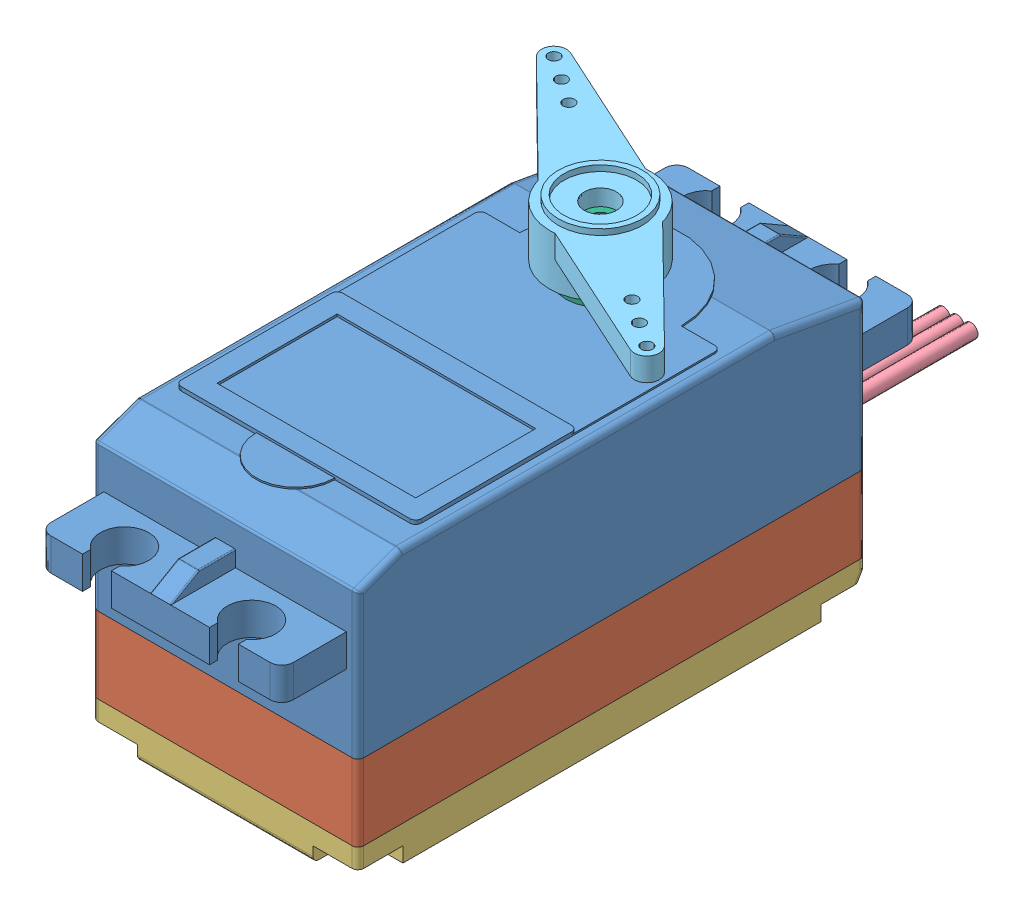
SolidWorks assembly MYSTERY SDS-S0070, ANALOG SERVO, configuration Default. Lengths in mm.
Overall size (32.51 30.1 69).
10 component instances, 7 part files, 17 mates.
Components (placement in the parent):
- MYSTERY SDS-S0070, ANALOG SERVO, MAIN BODY, TOP-1: MYSTERY SDS-S0070, ANALOG SERVO, MAIN BODY, TOP [Default] at origin size (23 14.34 55.2)
- MYSTERY SDS-S0070, ANALOG SERVO, MAIN BODY, MIDDLE-1: MYSTERY SDS-S0070, ANALOG SERVO, MAIN BODY, MIDDLE [Default] at (0 -3.3 0) size (23 6.6 44)
- MYSTERY SDS-S0070, ANALOG SERVO, MAIN BODY, BOTTOM-1: MYSTERY SDS-S0070, ANALOG SERVO, MAIN BODY, BOTTOM [Default] at (0 -9.6 0) size (23 3 44)
- MYSTERY SDS-S0070, ANALOG SERVO, CONNECTOR-1: MYSTERY SDS-S0070, ANALOG SERVO, CONNECTOR [Default] at (0 -4.55 -22) size (6.8 4.1 19.4)
- MYSTERY SDS-S0070, ANALOG SERVO, HORN-1: MYSTERY SDS-S0070, ANALOG SERVO, HORN [Default] at (0 15.6 -10.5) x (0.566638 0 -0.823967) z (0.823967 0 0.566638) size (8.8 4.9 33.4)
- MYSTERY SDS-S0070, ANALOG SERVO, SHAFT-1: MYSTERY SDS-S0070, ANALOG SERVO, SHAFT [Default] at (0 0 -10.5) x (0.566638 0 -0.823967) z (0.823967 0 0.566638) size (5.8 18.6 5.8)
- MYSTERY SDS-S0070, ANALOG SERVO, M2X6, PAN HEAD PHILLIPS MACHINE SCREW,-1: MYSTERY SDS-S0070, ANALOG SERVO, M2X6, PAN HEAD PHILLIPS MACHINE SCREW, [default] at (9.3 -1.9 19.8) x (0.961815 0 -0.273699) z (0 1 0) size (3 3 6.98)
- MYSTERY SDS-S0070, ANALOG SERVO, M2X6, PAN HEAD PHILLIPS MACHINE SCREW,-2: MYSTERY SDS-S0070, ANALOG SERVO, M2X6, PAN HEAD PHILLIPS MACHINE SCREW, [default] at (-9.3 -1.9 19.8) x (-0.961815 0 -0.273699) z (0 1 0) size (3 3 6.98)
- MYSTERY SDS-S0070, ANALOG SERVO, M2X6, PAN HEAD PHILLIPS MACHINE SCREW,-3: MYSTERY SDS-S0070, ANALOG SERVO, M2X6, PAN HEAD PHILLIPS MACHINE SCREW, [default] at (9.3 -1.9 -19.8) x (0.961815 0 0.273699) z (0 1 0) size (3 3 6.98)
- MYSTERY SDS-S0070, ANALOG SERVO, M2X6, PAN HEAD PHILLIPS MACHINE SCREW,-4: MYSTERY SDS-S0070, ANALOG SERVO, M2X6, PAN HEAD PHILLIPS MACHINE SCREW, [default] at (-9.3 -1.9 -19.8) x (-0.961815 0 0.273699) z (0 1 0) size (3 3 6.98)
Mates (geometry in assembly coordinates):
- Coincident5: coincident: plane of assembly through (0 0 0) normal (1 0 0); plane of MYSTERY SDS-S0070, ANALOG SERVO, MAIN BODY, BOTTOM-1 through (0 -9.6 0) normal (1 0 0); plane of assembly
- Coincident6: coincident: plane of assembly through (0 0 0) normal (0 0 1); plane of MYSTERY SDS-S0070, ANALOG SERVO, MAIN BODY, BOTTOM-1 through (0 -9.6 0) normal (0 0 1); plane of assembly
- Coincident142: coordinate: point of assembly; point of MYSTERY SDS-S0070, ANALOG SERVO, MAIN BODY, TOP-1; point of assembly
- Coincident143: coincident: plane of assembly through (0 0 0) normal (1 0 0); plane of MYSTERY SDS-S0070, ANALOG SERVO, MAIN BODY, MIDDLE-1 through (0 -3.3 0) normal (1 0 0); plane of assembly
- Coincident144: coincident: plane of assembly through (0 0 0) normal (0 0 1); plane of MYSTERY SDS-S0070, ANALOG SERVO, MAIN BODY, MIDDLE-1 through (0 -3.3 0) normal (0 0 1); plane of assembly
- Coincident145: coincident: plane of assembly; plane of assembly; plane of MYSTERY SDS-S0070, ANALOG SERVO, MAIN BODY, MIDDLE-1 through (0 -6.6 0) normal (0 -1 0); plane of MYSTERY SDS-S0070, ANALOG SERVO, MAIN BODY, BOTTOM-1 through (0 -6.6 0) normal (0 1 0)
- Coincident146: coincident: plane of assembly; plane of assembly; plane of MYSTERY SDS-S0070, ANALOG SERVO, MAIN BODY, TOP-1 through (0 0 0) normal (0 -1 0); plane of MYSTERY SDS-S0070, ANALOG SERVO, MAIN BODY, MIDDLE-1 through (0 0 0) normal (0 1 0)
- Coincident147: coincident: plane of assembly; plane of assembly; plane of MYSTERY SDS-S0070, ANALOG SERVO, MAIN BODY, MIDDLE-1 through (-11.5 0 -22) normal (0 0 -1); plane of MYSTERY SDS-S0070, ANALOG SERVO, CONNECTOR-1 through (0 -4.55 -22) normal (0 0 1)
- Coincident148: coincident: plane of assembly through (0 0 0) normal (1 0 0); plane of MYSTERY SDS-S0070, ANALOG SERVO, CONNECTOR-1 through (0 -4.55 -22) normal (1 0 0); plane of assembly
- Coincident149: coincident: line of assembly; line of assembly; line of MYSTERY SDS-S0070, ANALOG SERVO, MAIN BODY, BOTTOM-1 through (11 -6.6 -22) axis (-1 0 0); line of MYSTERY SDS-S0070, ANALOG SERVO, CONNECTOR-1 through (-2.9 -6.6 -22) axis (1 0 0)
- Concentric1: concentric: cylinder of assembly; cylinder of assembly; cylinder of MYSTERY SDS-S0070, ANALOG SERVO, MAIN BODY, TOP-1 through (0 0 -10.5) axis (0 1 0) radius 3; cylinder of MYSTERY SDS-S0070, ANALOG SERVO, SHAFT-1 through (0 14.6 -10.5) axis (0 -1 0) radius 2.9
- Coincident150: coincident: plane of assembly; plane of assembly; plane of MYSTERY SDS-S0070, ANALOG SERVO, MAIN BODY, TOP-1 through (0 0 0) normal (0 -1 0); plane of MYSTERY SDS-S0070, ANALOG SERVO, SHAFT-1 through (0 0 -10.5) normal (0 -1 0)
- Concentric2: concentric: cylinder of assembly; cylinder of assembly; cylinder of MYSTERY SDS-S0070, ANALOG SERVO, HORN-1 through (0 15.6 -10.5) axis (0 1 0) radius 1.4; cylinder of MYSTERY SDS-S0070, ANALOG SERVO, SHAFT-1 through (0 14.6 -10.5) axis (0 1 0) radius 0.8
- Coincident151: coincident: plane of assembly; plane of assembly; plane of MYSTERY SDS-S0070, ANALOG SERVO, HORN-1 through (0 15.6 -10.5) normal (0.566638 0 -0.823967); plane of MYSTERY SDS-S0070, ANALOG SERVO, SHAFT-1 through (0 0 -10.5) normal (0.566638 0 -0.823967)
- Coincident152: coincident: plane of assembly; plane of assembly; plane of MYSTERY SDS-S0070, ANALOG SERVO, HORN-1 through (0 18.6 -10.5) normal (0 -1 0); plane of MYSTERY SDS-S0070, ANALOG SERVO, SHAFT-1 through (0 18.6 -10.5) normal (0 1 0)
- Concentric3: concentric: cylinder of assembly; cylinder of assembly; cylinder of MYSTERY SDS-S0070, ANALOG SERVO, MAIN BODY, BOTTOM-1 through (9.3 -8.3 19.8) axis (0 -1 0) radius 1.6; cylinder of MYSTERY SDS-S0070, ANALOG SERVO, M2X6, PAN HEAD PHILLIPS MACHINE SCREW,-1 through (9.3 -8.9 19.8) axis (0 1 0) radius 1.5
- Coincident153: coincident: plane of assembly; plane of assembly; plane of MYSTERY SDS-S0070, ANALOG SERVO, MAIN BODY, BOTTOM-1 through (10.35 -6.9 19.8) normal (0 -1 0); plane of MYSTERY SDS-S0070, ANALOG SERVO, M2X6, PAN HEAD PHILLIPS MACHINE SCREW,-1 through (9.3 -6.9 19.8) normal (0 1 0)
